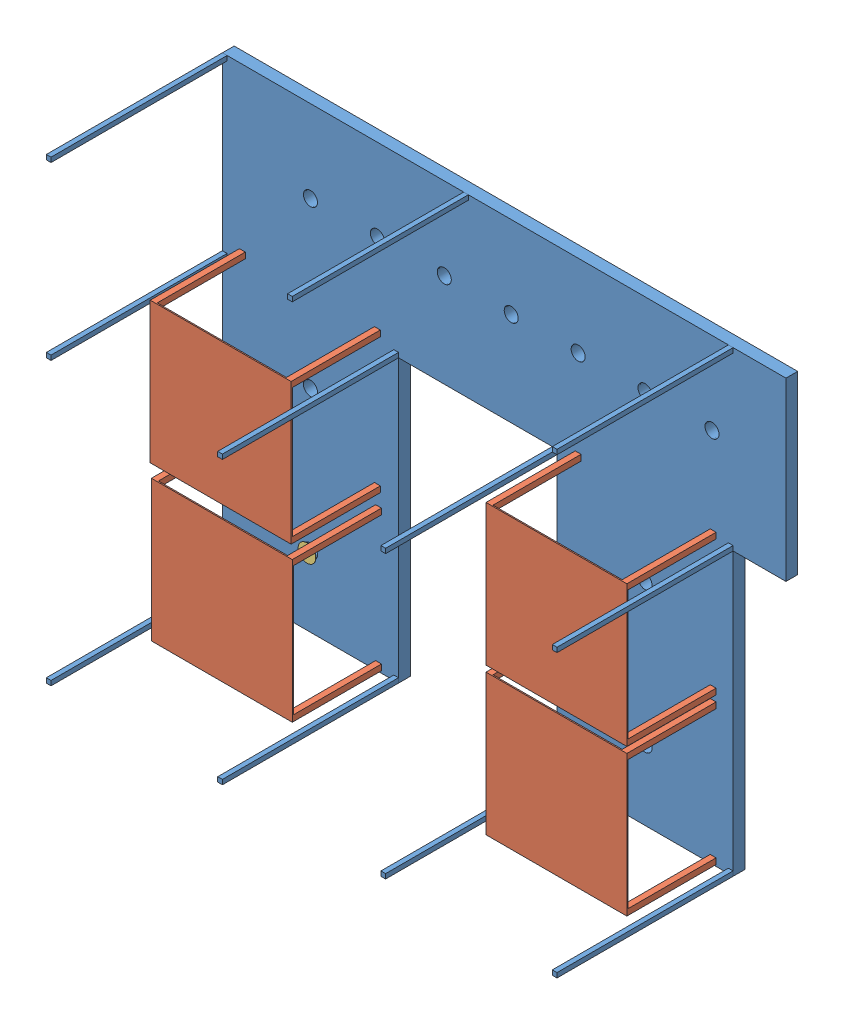
SolidWorks assembly Assemb_rack, configuration Default. Lengths in mm.
Overall size (4800 3900 1600).
26 component instances, 4 part files, 20 mates.
Components (placement in the parent):
- Rack-1: Rack [Default] at (-3510.396 2282.4992 6606.976) size (4800 3900 1600)
- for_RACK-1: for_RACK [Default] at (-3365.396 4810.124 7466.976) x (-1 0 0) z (0 0 -1) size (1200 1200 760)
- for_RACK-2: for_RACK [Default] at (-3355.396 3501.4532 7466.976) x (-1 0 0) z (0 0 -1) size (1200 1200 760)
- for_RACK-3: for_RACK [Default] at (-505.396 3496.4995 7466.976) x (-1 0 0) z (0 0 -1) size (1200 1200 760)
- for_RACK-4: for_RACK [Default] at (-505.396 4748.1188 7466.976) x (-1 0 0) z (0 0 -1) size (1200 1200 760)
- cover_for_rack-1: cover_for_rack [Default] at (-2760.396 2882.4992 6736.976) x (0.923728 0.383049 0) z (0 0 -1) size (150 150 16)
- Bolt-21: Bolt [Default] at (799.604 2322.4992 6705.9965) x (0 0 1) z (-0.990521 0.137362 0) (suppressed, hidden)
- Bolt-22: Bolt [Default] at (-610.396 2322.4992 6705.9965) x (0 0 1) z (-0.990521 0.137362 0) (suppressed, hidden)
- Bolt-23: Bolt [Default] at (799.604 3122.4992 6705.9965) x (0 0 1) z (-0.990521 0.137362 0) (suppressed, hidden)
- Bolt-24: Bolt [Default] at (-610.396 3122.4992 6705.9965) x (0 0 1) z (-0.990521 0.137362 0) (suppressed, hidden)
- Bolt-25: Bolt [Default] at (799.604 3922.4992 6705.9965) x (0 0 1) z (-0.990521 0.137362 0) (suppressed, hidden)
- Bolt-26: Bolt [Default] at (-610.396 3922.4992 6705.9965) x (0 0 1) z (-0.990521 0.137362 0) (suppressed, hidden)
- Bolt-27: Bolt [Default] at (799.604 4722.4992 6705.9965) x (0 0 1) z (-0.990521 0.137362 0) (suppressed, hidden)
- Bolt-28: Bolt [Default] at (-610.396 4722.4992 6705.9965) x (0 0 1) z (-0.990521 0.137362 0) (suppressed, hidden)
- Bolt-31: Bolt [Default] at (799.604 6122.4992 6508.189) x (0 0 -1) z (1 0 0) (suppressed, hidden)
- Bolt-32: Bolt [Default] at (-610.396 6122.4992 6508.189) x (0 0 -1) z (1 0 0) (suppressed, hidden)
- Bolt-36: Bolt [Default] at (-2050.396 2322.4992 6508.189) x (0 0 -1) z (1 0 0) (suppressed, hidden)
- Bolt-37: Bolt [Default] at (-2050.396 3122.4992 6508.189) x (0 0 -1) z (1 0 0) (suppressed, hidden)
- Bolt-38: Bolt [Default] at (-2050.396 3922.4992 6508.189) x (0 0 -1) z (1 0 0) (suppressed, hidden)
- Bolt-39: Bolt [Default] at (-2050.396 4722.4992 6508.189) x (0 0 -1) z (1 0 0) (suppressed, hidden)
- Bolt-40: Bolt [Default] at (-3470.396 2322.4992 6508.189) x (0 0 -1) z (1 0 0) (suppressed, hidden)
- Bolt-41: Bolt [Default] at (-3470.396 3122.4992 6508.189) x (0 0 -1) z (1 0 0) (suppressed, hidden)
- Bolt-42: Bolt [Default] at (-3470.396 3922.4992 6508.189) x (0 0 -1) z (1 0 0) (suppressed, hidden)
- Bolt-43: Bolt [Default] at (-3470.396 4722.4992 6508.189) x (0 0 -1) z (1 0 0) (suppressed, hidden)
- Bolt-44: Bolt [Default] at (-2050.396 6122.4992 6508.189) x (0 0 -1) z (1 0 0) (suppressed, hidden)
- Bolt-45: Bolt [Default] at (-3460.396 6122.4992 6508.189) x (0 0 -1) z (1 0 0) (suppressed, hidden)
Mates (geometry in assembly coordinates):
- Coincident1: coincident anti-aligned: plane of Rack-1 through (-3510.396 2282.4992 6706.976) normal (0 0 1); plane of for_RACK-1 through (-3365.396 4810.124 6706.976) normal (0 0 -1)
- Distance1: distance = 155 mm aligned: plane of for_RACK-1 through (-2165.396 4810.124 7456.976) normal (1 0 0); plane of Rack-1 through (-2010.396 4682.4992 6706.976) normal (1 0 0)
- Coincident3: coincident anti-aligned: plane of Rack-1 through (-3510.396 2282.4992 6706.976) normal (0 0 1); plane of for_RACK-2 through (-3355.396 3501.4532 6706.976) normal (0 0 -1)
- Distance2: distance = 155 mm aligned: plane of for_RACK-2 through (-3355.396 3501.4532 7456.976) normal (-1 0 0); plane of Rack-1 through (-3510.396 2282.4992 6706.976) normal (-1 0 0)
- Coincident5: coincident anti-aligned: plane of Rack-1 through (-3510.396 2282.4992 6706.976) normal (0 0 1); plane of for_RACK-3 through (-505.396 3496.4995 6706.976) normal (0 0 -1)
- Distance3: distance = 155 mm aligned: plane of for_RACK-3 through (-505.396 3496.4995 7456.976) normal (-1 0 0); plane of Rack-1 through (-660.396 2282.4992 6706.976) normal (-1 0 0)
- Coincident7: coincident anti-aligned: plane of Rack-1 through (-3510.396 2282.4992 6706.976) normal (0 0 1); plane of for_RACK-4 through (-505.396 4748.1188 6706.976) normal (0 0 -1)
- Distance4: distance = 155 mm aligned: plane of for_RACK-4 through (-505.396 4748.1188 7456.976) normal (-1 0 0); plane of Rack-1 through (-660.396 2282.4992 6706.976) normal (-1 0 0)
- Distance5: distance = 40 mm aligned: plane of Bolt-21 through (801.115 2333.395 6566.976) normal (0 0 -1); plane of Rack-1 through (-3510.396 2282.4992 6606.976) normal (0 0 -1)
- Concentric1: concentric aligned: circle of Bolt-21; circle of assembly
- Concentric3: concentric anti-aligned: circle of Bolt-31; circle of assembly
- Distance6: distance = 40 mm aligned: plane of Rack-1 through (-3510.396 2282.4992 6606.976) normal (0 0 -1); plane of Bolt-31 through (799.604 6122.4992 6566.976) normal (0 0 -1)
- Concentric4: concentric anti-aligned: circle of Bolt-36; circle of assembly
- Distance7: distance = 40 mm aligned: plane of Bolt-36 through (-2050.396 2322.4992 6566.976) normal (0 0 -1); plane of Rack-1 through (-3510.396 2282.4992 6606.976) normal (0 0 -1)
- Concentric5: concentric anti-aligned: circle of Bolt-40; circle of assembly
- Distance8: distance = 40 mm aligned: plane of Rack-1 through (-3510.396 2282.4992 6606.976) normal (0 0 -1); plane of Bolt-40 through (-3470.396 2322.4992 6566.976) normal (0 0 -1)
- Concentric6: concentric anti-aligned: circle of Bolt-44; circle of assembly
- Distance9: distance = 40 mm aligned: plane of Bolt-44 through (-2050.396 6122.4992 6566.976) normal (0 0 -1); plane of Rack-1 through (-3510.396 2282.4992 6606.976) normal (0 0 -1)
- Concentric7: concentric anti-aligned: circle of Rack-1; circle of cover_for_rack-1
- Distance10: distance = 30 mm aligned: plane of cover_for_rack-1 through (-2760.396 2882.4992 6736.976) normal (0 0 1); plane of Rack-1 through (-3510.396 2282.4992 6706.976) normal (0 0 1)
